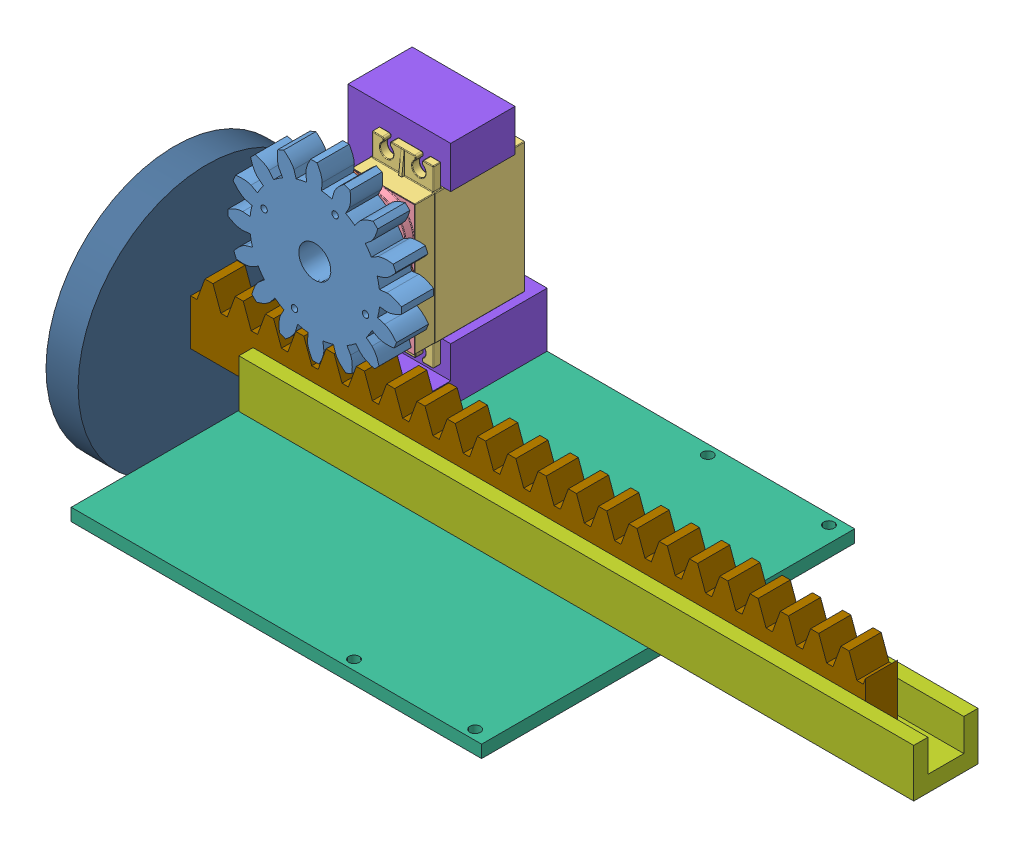
SolidWorks assembly Rack and Gear Assembly, configuration Default. Lengths in mm.
Overall size (239.43 122.37 116.1).
11 component instances, 10 part files, 16 mates.
Components (placement in the parent):
- Gear v1-1: Gear v1 [Default] at (-70.0431 -14.9603 72.2447) x (0.928193 -0.372098 0) z (0 0 1) size (54 54 10)
- Servo Futaba S3003 v6.step-1: Servo Futaba S3003 v6.step [Default] at (-69.9819 -25.7674 24.9447) x (0 1 0) z (1 0 0) size (56.04 47.8 36.5)
  - Aspa-creu-Axix holder.step-1: Aspa-creu-Axix holder.step [Default] at (10.536 47.3 0) x (-1 0 0) z (0 0 1) size (36.5 6.1 36.5)
  - Servo Futaba S3003.step-1: Servo Futaba S3003.step [Default] at origin size (54.5 35.94 20)
  - Servo Futaba S3003-0.step-1: Servo Futaba S3003-0.step [Default] at origin size (40.52 4.26 19.75)
  - Servo Futaba S3003-1.step-1: Servo Futaba S3003-1.step [Default] at origin size (5.7 4.5 5.7)
- Base-1: Base [Default] at (-9.4819 -66.9174 22.4447) x (0 0 1) z (-1 0 0) size (116.1 3.9 127.7)
- Sider-1: Sider [Default] at (-89.2051 -63.0174 86.6447) size (210 15 20)
- Servo Holder-1: Servo Holder [Default] at (-82.4819 -71.0174 62.4447) size (32 71 40)
- Rack Extend-1: Rack Extend [Default] at (-3.6315 -40.0174 72.2447) size (210 21 10)
- ChickiesLogo-1: ChickiesLogo [Default] at (-118.6315 -70.9257 67.7253) x (0 0.354054 0.935225) z (-1 0 0) size (80 80 10)
Mates (geometry in assembly coordinates):
- Coincident1: coincident anti-aligned: plane of Gear v1-1 through (-69.9819 -15.2314 72.2447) normal (0 0 -1); plane of Servo Futaba S3003 v6.step-1/Aspa-creu-Axix holder.step-1 through (-69.9819 -15.2314 72.2447) normal (0 0 1)
- Concentric4: concentric aligned: circle of Gear v1-1; circle of Servo Futaba S3003 v6.step-1/Aspa-creu-Axix holder.step-1
- Coincident12: coincident anti-aligned: plane of Sider-1 through (-89.2051 -58.0174 86.6447) normal (0 1 0); plane of Rack Extend-1 through (-3.6315 -58.0174 72.2447) normal (0 -1 0)
- Coincident17: coincident aligned: plane of Gear v1-1 through (-69.9819 -15.2314 82.2447) normal (0 0 1); plane of Rack Extend-1 through (-3.6315 -40.0174 82.2447) normal (0 0 1)
- Coincident18: coincident anti-aligned: plane of Base-1 through (-9.4819 -63.0174 22.4447) normal (0 1 0); plane of Sider-1 through (-89.2051 -63.0174 86.6447) normal (0 -1 0)
- Coincident19: coincident anti-aligned: plane of Servo Futaba S3003 v6.step-1/Servo Futaba S3003.step-1 through (-69.9819 -25.7674 52.4447) normal (0 0 -1); plane of Servo Holder-1 through (-82.4819 -71.0174 52.4447) normal (0 0 1)
- Coincident20: coincident anti-aligned: plane of Servo Futaba S3003 v6.step-1/Servo Futaba S3003.step-1 through (-79.9819 -46.0174 26.9447) normal (0 -1 0); plane of Servo Holder-1 through (-82.4819 -46.0174 62.4447) normal (0 1 0)
- Coincident21: coincident anti-aligned: plane of Servo Futaba S3003 v6.step-1/Servo Futaba S3003.step-1 through (-79.9819 -5.5174 26.9447) normal (-1 0 0); plane of Servo Holder-1 through (-79.9819 -46.0174 62.4447) normal (1 0 0)
- Concentric5: concentric anti-aligned: circle of Rack Extend-1; circle of ChickiesLogo-1
- Coincident26: coincident anti-aligned: plane of Rack Extend-1 through (-108.6315 -48.0174 82.2447) normal (-1 0 0); plane of ChickiesLogo-1 through (-108.6315 -50.9174 77.2447) normal (1 0 0)
- Coincident27: coincident aligned: plane of Gear v1-1 through (-69.9819 -15.2314 82.2447) normal (0 0 1); plane of Rack Extend-1 through (-3.6315 -40.0174 82.2447) normal (0 0 1)
- Coincident28: coincident anti-aligned: plane of Sider-1 through (-89.2051 -63.0174 82.2447) normal (0 0 -1); plane of Rack Extend-1 through (-3.6315 -40.0174 82.2447) normal (0 0 1)
- Parallel1: parallel aligned: plane of Base-1 through (-9.4819 -63.0174 22.4447) normal (0 0 -1); plane of Sider-1 through (-89.2051 -48.0174 66.6447) normal (0 0 -1)
- Coincident32: coincident aligned: plane of Base-1 through (-89.4819 -66.9174 22.4447) normal (-1 0 0); plane of Servo Holder-1 through (-89.4819 -71.0174 62.4447) normal (-1 0 0)
- Coincident33: coincident aligned: plane of Base-1 through (-9.4819 -63.0174 22.4447) normal (0 0 -1); plane of Servo Holder-1 through (-82.4819 -21.0174 22.4447) normal (0 0 -1)
- Coincident34: coincident anti-aligned: plane of Base-1 through (-9.4819 -63.0174 22.4447) normal (0 1 0); plane of Servo Holder-1 through (-82.4819 -63.0174 62.4447) normal (0 -1 0)
